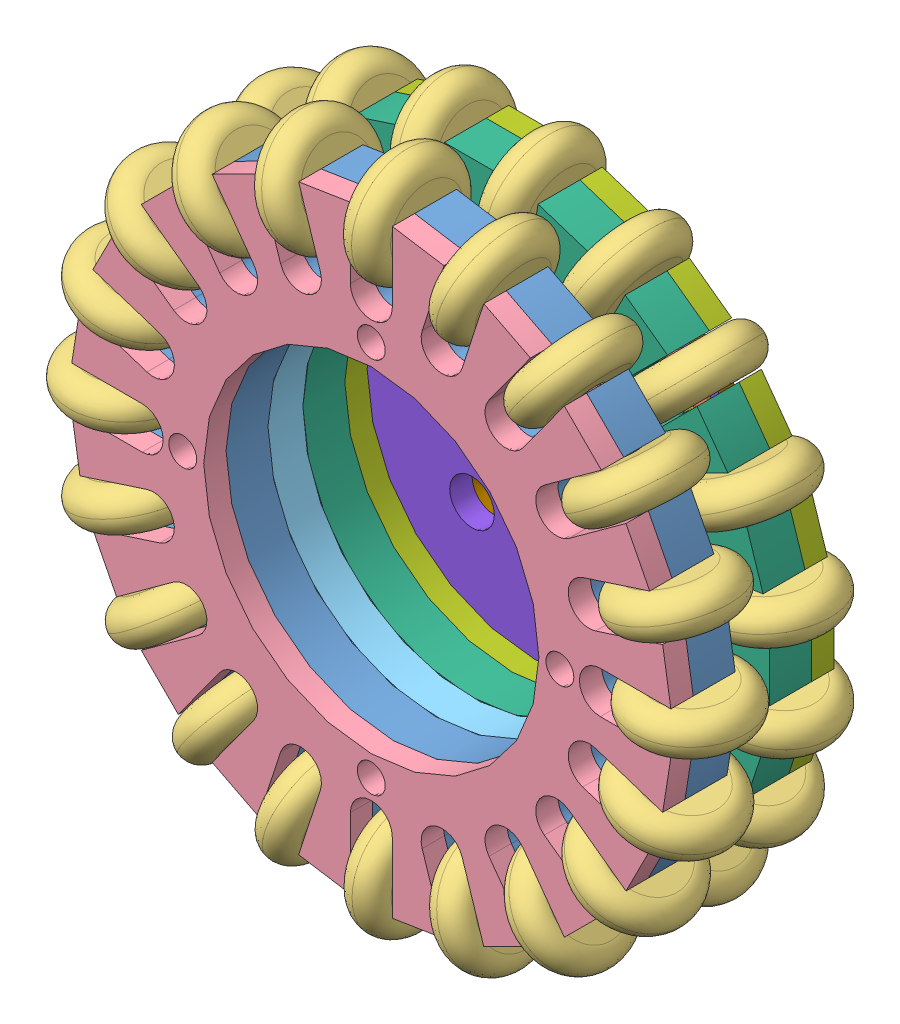
SolidWorks assembly Wheel 2.0, configuration Default. Lengths in mm.
Overall size (60.66 60.66 19.7).
49 component instances, 9 part files, 26 mates.
Components (placement in the parent):
- Wheel Plate 2.2-1: Wheel Plate 2.2 [Default] at (18.3786 25.0187 28.3875) size (42.9 42.9 3)
- Wheel 2.0 Ring-2: Wheel 2.0 Ring [Default] at (18.3786 25.0187 29.3875) x (0.999997 0.002505 0) z (0 0 1) size (41 41 1)
- Inner Wheel - GTF-1: Inner Wheel - GTF [Default] at (16.9562 45.2287 30.3875) x (0 0 -1) z (1 0 0) size (8 8 2.8)
- Inner Wheel - GTF-2: Inner Wheel - GTF [Default] at (10.7806 43.8 30.3875) x (0 0 -1) z (0.951057 0.309017 0) size (8 8 2.8)
- Inner Wheel - GTF-3: Inner Wheel - GTF [Default] at (5.3487 40.5329 30.3875) x (0 0 -1) z (0.809017 0.587785 0) size (8 8 2.8)
- Inner Wheel - GTF-4: Inner Wheel - GTF [Default] at (1.1923 35.7471 30.3875) x (0 0 -1) z (0.587785 0.809017 0) size (8 8 2.8)
- Inner Wheel - GTF-5: Inner Wheel - GTF [Default] at (-1.2818 29.9112 30.3875) x (0 0 -1) z (0.309017 0.951057 0) size (8 8 2.8)
- Inner Wheel - GTF-6: Inner Wheel - GTF [Default] at (-1.8314 23.5963 30.3875) x (0 0 -1) z (0 1 0) size (8 8 2.8)
- Inner Wheel - GTF-7: Inner Wheel - GTF [Default] at (-0.4027 17.4207 30.3875) x (0 0 -1) z (-0.309017 0.951057 0) size (8 8 2.8)
- Inner Wheel - GTF-8: Inner Wheel - GTF [Default] at (2.8644 11.9888 30.3875) x (0 0 -1) z (-0.587785 0.809017 0) size (8 8 2.8)
- Inner Wheel - GTF-9: Inner Wheel - GTF [Default] at (7.6502 7.8324 30.3875) x (0 0 -1) z (-0.809017 0.587785 0) size (8 8 2.8)
- Inner Wheel - GTF-10: Inner Wheel - GTF [Default] at (13.4862 5.3583 30.3875) x (0 0 -1) z (-0.951057 0.309017 0) size (8 8 2.8)
- Inner Wheel - GTF-11: Inner Wheel - GTF [Default] at (19.801 4.8087 30.3875) x (0 0 -1) z (-1 0 0) size (8 8 2.8)
- Inner Wheel - GTF-12: Inner Wheel - GTF [Default] at (25.9766 6.2374 30.3875) x (0 0 -1) z (-0.951057 -0.309017 0) size (8 8 2.8)
- Inner Wheel - GTF-13: Inner Wheel - GTF [Default] at (31.4085 9.5045 30.3875) x (0 0 -1) z (-0.809017 -0.587785 0) size (8 8 2.8)
- Inner Wheel - GTF-14: Inner Wheel - GTF [Default] at (35.5649 14.2903 30.3875) x (0 0 -1) z (-0.587785 -0.809017 0) size (8 8 2.8)
- Inner Wheel - GTF-15: Inner Wheel - GTF [Default] at (38.039 20.1263 30.3875) x (0 0 -1) z (-0.309017 -0.951057 0) size (8 8 2.8)
- Inner Wheel - GTF-16: Inner Wheel - GTF [Default] at (38.5886 26.4411 30.3875) x (0 0 -1) z (0 -1 0) size (8 8 2.8)
- Inner Wheel - GTF-17: Inner Wheel - GTF [Default] at (37.1599 32.6168 30.3875) x (0 0 -1) z (0.309017 -0.951057 0) size (8 8 2.8)
- Inner Wheel - GTF-18: Inner Wheel - GTF [Default] at (33.8928 38.0486 30.3875) x (0 0 -1) z (0.587785 -0.809017 0) size (8 8 2.8)
- Inner Wheel - GTF-19: Inner Wheel - GTF [Default] at (29.107 42.205 30.3875) x (0 0 -1) z (0.809017 -0.587785 0) size (8 8 2.8)
- Inner Wheel - GTF-20: Inner Wheel - GTF [Default] at (23.271 44.6791 30.3875) x (0 0 -1) z (0.951057 -0.309017 0) size (8 8 2.8)
- Wheel Plate 2.1-1: Wheel Plate 2.1 [Default] at (18.3786 25.0187 31.3875) size (42.9 42.9 1.6)
- Spacer 2.0-1: Spacer 2.0 [Default] at (18.3786 25.0187 25.8875) size (30 30 2.5)
- Wheel Plate 2.4-1: Wheel Plate 2.4 [Default] at (18.3786 25.0187 25.8875) x (-0.707107 -0.707107 0) z (0 0 -1) size (42.9 42.9 3)
- Wheel 2.0 Ring-3: Wheel 2.0 Ring [Default] at (18.3786 25.0187 23.8875) x (0.898558 0.438855 0) z (0 0 1) size (41 41 1)
- Inner Wheel - GTF-22: Inner Wheel - GTF [Default] at (37.9749 29.5666 23.8875) x (0.987108 0.156343 0.034273) z (0.156434 -0.987688 0) size (8 8 2.8)
- Inner Wheel - GTF-23: Inner Wheel - GTF [Default] at (38.4212 23.2884 23.8875) x (0.987108 -0.156343 0.034273) z (-0.156434 -0.987688 0) size (8 8 2.8)
- Inner Wheel - GTF-24: Inner Wheel - GTF [Default] at (36.9055 17.1796 23.8875) x (0.890483 -0.453724 0.034273) z (-0.45399 -0.891007 0) size (8 8 2.8)
- Inner Wheel - GTF-25: Inner Wheel - GTF [Default] at (33.5763 11.8381 23.8875) x (0.706691 -0.706691 0.034273) z (-0.707107 -0.707107 0) size (8 8 2.8)
- Inner Wheel - GTF-26: Inner Wheel - GTF [Default] at (28.7595 7.7869 23.8875) x (0.453724 -0.890483 0.034273) z (-0.891007 -0.45399 0) size (8 8 2.8)
- Inner Wheel - GTF-27: Inner Wheel - GTF [Default] at (22.9265 5.4224 23.8875) x (0.156343 -0.987108 0.034273) z (-0.987688 -0.156434 0) size (8 8 2.8)
- Inner Wheel - GTF-28: Inner Wheel - GTF [Default] at (16.6483 4.9762 23.8875) x (-0.156343 -0.987108 0.034273) z (-0.987688 0.156434 0) size (8 8 2.8)
- Inner Wheel - GTF-29: Inner Wheel - GTF [Default] at (10.5395 6.4918 23.8875) x (-0.453724 -0.890483 0.034273) z (-0.891007 0.45399 0) size (8 8 2.8)
- Inner Wheel - GTF-30: Inner Wheel - GTF [Default] at (5.198 9.821 23.8875) x (-0.706691 -0.706691 0.034273) z (-0.707107 0.707107 0) size (8 8 2.8)
- Inner Wheel - GTF-31: Inner Wheel - GTF [Default] at (1.1468 14.6379 23.8875) x (-0.890483 -0.453724 0.034273) z (-0.45399 0.891007 0) size (8 8 2.8)
- Inner Wheel - GTF-32: Inner Wheel - GTF [Default] at (-1.2177 20.4709 23.8875) x (-0.987108 -0.156343 0.034273) z (-0.156434 0.987688 0) size (8 8 2.8)
- Inner Wheel - GTF-33: Inner Wheel - GTF [Default] at (-1.664 26.7491 23.8875) x (-0.987108 0.156343 0.034273) z (0.156434 0.987688 0) size (8 8 2.8)
- Inner Wheel - GTF-34: Inner Wheel - GTF [Default] at (-0.1483 32.8579 23.8875) x (-0.890483 0.453724 0.034273) z (0.45399 0.891007 0) size (8 8 2.8)
- Inner Wheel - GTF-35: Inner Wheel - GTF [Default] at (3.1809 38.1993 23.8875) x (-0.706691 0.706691 0.034273) z (0.707107 0.707107 0) size (8 8 2.8)
- Inner Wheel - GTF-36: Inner Wheel - GTF [Default] at (7.9977 42.2506 23.8875) x (-0.453724 0.890483 0.034273) z (0.891007 0.45399 0) size (8 8 2.8)
- Inner Wheel - GTF-37: Inner Wheel - GTF [Default] at (13.8307 44.615 23.8875) x (-0.156343 0.987108 0.034273) z (0.987688 0.156434 0) size (8 8 2.8)
- Inner Wheel - GTF-38: Inner Wheel - GTF [Default] at (20.1089 45.0613 23.8875) x (0.156343 0.987108 0.034273) z (0.987688 -0.156434 0) size (8 8 2.8)
- Inner Wheel - GTF-39: Inner Wheel - GTF [Default] at (26.2177 43.5456 23.8875) x (0.453724 0.890483 0.034273) z (0.891007 -0.45399 0) size (8 8 2.8)
- Inner Wheel - GTF-40: Inner Wheel - GTF [Default] at (31.5592 40.2164 23.8875) x (0.706691 0.706691 0.034273) z (0.707107 -0.707107 0) size (8 8 2.8)
- Inner Wheel - GTF-41: Inner Wheel - GTF [Default] at (35.6104 35.3996 23.8875) x (0.890483 0.453724 0.034273) z (0.45399 -0.891007 0) size (8 8 2.8)
- Wheel Plate 2.3-1: Wheel Plate 2.3 [Default] at (18.3786 25.0187 21.2875) x (0.707107 -0.707107 0) z (0 0 1) size (42.9 42.9 1.6)
- Cross 2.0-1: Cross 2.0 [Default] at (18.3786 25.0187 19.6875) size (30 30 1.6)
- Wheel Mounting-1: Wheel Mounting [Default] at (18.3786 25.0188 17.1874) size (19 19.01 5)
Mates (geometry in assembly coordinates):
- Concentric2: concentric anti-aligned: cylinder of Wheel Plate 2.2-1 through (18.3786 25.0187 31.3875) axis (0 0 -1) radius 12; circle of Wheel 2.0 Ring-2
- Tangent3: tangent anti-aligned: plane of Wheel Plate 2.2-1 through (18.3786 25.0187 29.3875) normal (0 0 1); torus of Wheel 2.0 Ring-2
- Tangent4: tangent anti-aligned: plane of Wheel Plate 2.2-1 through (18.3786 25.0187 29.3875) normal (0 0 1); cylinder of Inner Wheel - GTF-1 through (16.9562 45.2287 30.3875) axis (1 0 0) radius 1
- Coincident1: coincident anti-aligned: plane of Wheel Plate 2.2-1 through (18.3786 25.0187 31.3875) normal (0 0 1); plane of Wheel Plate 2.1-1 through (18.3786 25.0187 31.3875) normal (0 0 -1)
- Concentric3: concentric aligned: cylinder of Wheel Plate 2.2-1 through (18.3786 38.5187 31.3875) axis (0 0 -1) radius 1; cylinder of Wheel Plate 2.1-1 through (18.3786 38.5187 32.9875) axis (0 0 -1) radius 1
- Concentric4: concentric aligned: cylinder of Wheel Plate 2.2-1 through (18.3786 11.5187 31.3875) axis (0 0 -1) radius 1; cylinder of Wheel Plate 2.1-1 through (18.3786 11.5187 32.9875) axis (0 0 -1) radius 1
- Concentric5: concentric aligned: cylinder of Wheel Plate 2.2-1 through (18.3786 38.5187 31.3875) axis (0 0 -1) radius 1; cylinder of Spacer 2.0-1 through (18.3786 38.5187 26.8875) axis (0 0 -1) radius 1
- Concentric6: concentric aligned: cylinder of Wheel Plate 2.2-1 through (18.3786 11.5187 31.3875) axis (0 0 -1) radius 1; cylinder of Spacer 2.0-1 through (18.3786 11.5187 26.8875) axis (0 0 -1) radius 1
- Coincident4: coincident anti-aligned: plane of Wheel Plate 2.2-1 through (18.3786 25.0187 28.3875) normal (0 0 -1); plane of Spacer 2.0-1 through (18.3786 25.0187 28.3875) normal (0 0 1)
- Coincident5: coincident anti-aligned: plane of Spacer 2.0-1 through (18.3786 25.0187 25.8875) normal (0 0 -1); plane of Wheel Plate 2.4-1 through (18.3786 25.0187 25.8875) normal (0 0 1)
- Concentric7: concentric aligned: cylinder of Spacer 2.0-1 through (18.3786 38.5187 26.8875) axis (0 0 -1) radius 1; cylinder of Wheel Plate 2.4-1 through (18.3786 38.5187 32.8875) axis (0 0 -1) radius 1
- Concentric8: concentric aligned: cylinder of Spacer 2.0-1 through (18.3786 11.5187 26.8875) axis (0 0 -1) radius 1; cylinder of Wheel Plate 2.4-1 through (18.3786 11.5187 32.8875) axis (0 0 -1) radius 1
- Concentric9: concentric aligned: cylinder of Wheel Plate 2.4-1 through (18.3786 25.0187 22.8875) axis (0 0 1) radius 12; circle of Wheel 2.0 Ring-3
- Tangent5: tangent anti-aligned: plane of Wheel Plate 2.4-1 through (18.3786 25.0187 24.8875) normal (0 0 -1); torus of Wheel 2.0 Ring-3
- Tangent6: tangent anti-aligned: plane of Wheel Plate 2.4-1 through (18.3786 25.0187 24.8875) normal (0 0 -1); cylinder of Inner Wheel - GTF-22 through (37.9749 29.5666 23.8875) axis (0.156434 -0.987688 0) radius 1
- Lock2: lock: unknown of Wheel Plate 2.2-1; unknown of Inner Wheel - GTF-17
- Lock3: lock: unknown of Wheel Plate 2.4-1; unknown of Inner Wheel - GTF-22
- Coincident6: coincident anti-aligned: plane of Wheel Plate 2.4-1 through (18.3786 25.0187 22.8875) normal (0 0 -1); plane of Wheel Plate 2.3-1 through (18.3786 25.0187 22.8875) normal (0 0 1)
- Concentric12: concentric anti-aligned: cylinder of Wheel Plate 2.4-1 through (18.3786 38.5187 32.8875) axis (0 0 -1) radius 1; cylinder of Wheel Plate 2.3-1 through (18.3786 38.5187 12.8875) axis (0 0 1) radius 1
- Concentric13: concentric anti-aligned: cylinder of Wheel Plate 2.4-1 through (18.3786 11.5187 32.8875) axis (0 0 -1) radius 1; cylinder of Wheel Plate 2.3-1 through (18.3786 11.5187 12.8875) axis (0 0 1) radius 1
- Coincident7: coincident anti-aligned: plane of Wheel Plate 2.3-1 through (18.3786 25.0187 21.2875) normal (0 0 -1); plane of Cross 2.0-1 through (18.3786 25.0187 21.2875) normal (0 0 1)
- Concentric14: concentric anti-aligned: cylinder of Wheel Plate 2.3-1 through (18.3786 38.5187 12.8875) axis (0 0 1) radius 1; cylinder of Cross 2.0-1 through (18.3786 38.5187 21.2875) axis (0 0 -1) radius 1
- Concentric15: concentric anti-aligned: cylinder of Wheel Plate 2.3-1 through (18.3786 11.5187 12.8875) axis (0 0 1) radius 1; cylinder of Cross 2.0-1 through (18.3786 11.5187 21.2875) axis (0 0 -1) radius 1
- Concentric16: concentric aligned: cylinder of Cross 2.0-1 through (13.8885 29.5089 21.2875) axis (0 0 -1) radius 1.6; cylinder of Wheel Mounting-1 through (13.8885 29.5089 14.6875) axis (0 0 -1) radius 1.1303
- Concentric17: concentric aligned: cylinder of Cross 2.0-1 through (22.8687 20.5286 21.2875) axis (0 0 -1) radius 1.6; cylinder of Wheel Mounting-1 through (22.8687 20.5286 14.6875) axis (0 0 -1) radius 1.1303
- Coincident8: coincident anti-aligned: plane of Cross 2.0-1 through (18.3786 25.0187 19.6875) normal (0 0 -1); plane of Wheel Mounting-1 through (18.3786 25.0187 19.6875) normal (0 0 1)
